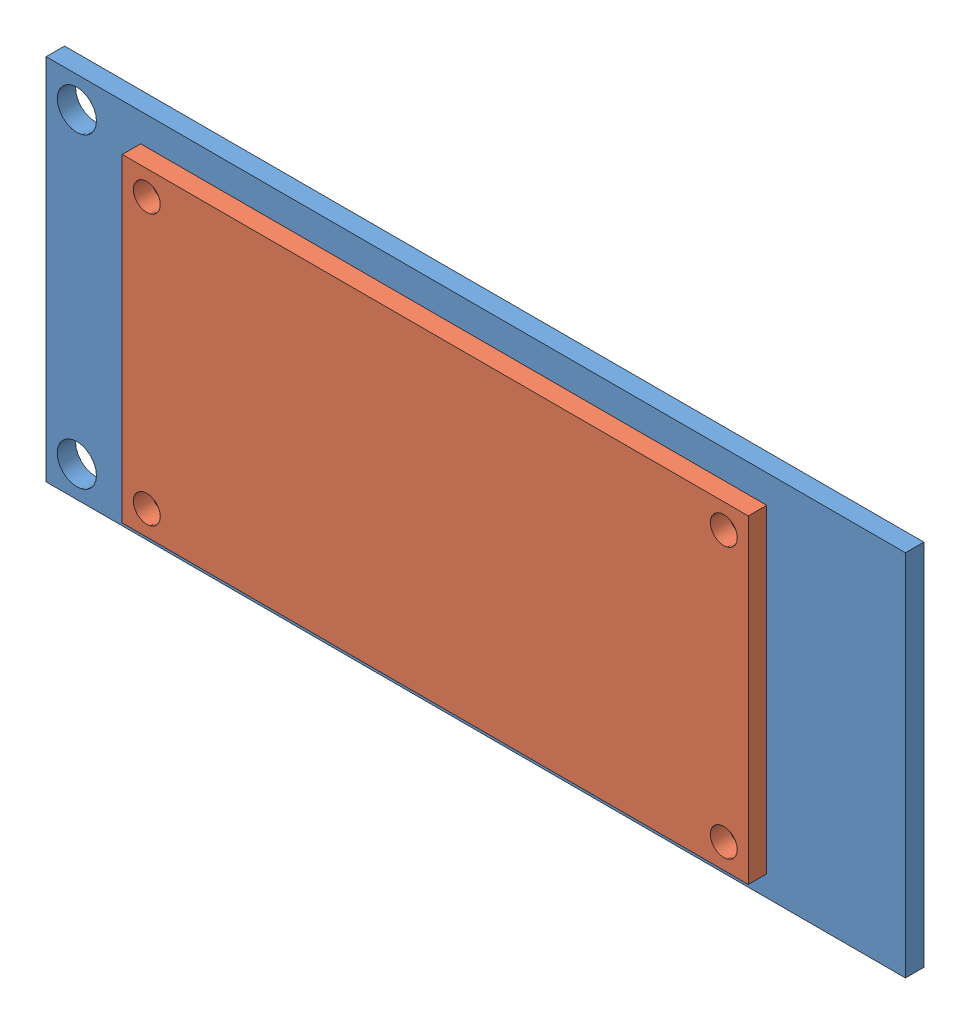
SolidWorks assembly DCDCSB, configuration По умолчанию. Lengths in mm.
Overall size (71.39 30 3.3).
2 component instances, 2 part files, 3 mates.
Components (placement in the parent):
- PodkladkaDCDC-2: PodkladkaDCDC [По умолчанию] x (1 0 0) z (0 -1 0) size (71.39 1.5 30)
- DCDC-1: DCDC [По умолчанию] at (8 2 1.8) x (1 0 0) z (0 -1 0) size (51 1.5 26)
Mates (geometry in assembly coordinates):
- Расстояние1: distance = 0.3 mm anti-aligned: plane of DCDC-1 through (8 2 1.8) normal (0 0 -1); plane of PodkladkaDCDC-2 through (0 0 1.5) normal (0 0 1)
- Концентричный1: concentric aligned: cylinder of PodkladkaDCDC-2 through (10 4 1.5) axis (0 0 -1) radius 1.1; cylinder of DCDC-1 through (10 4 3.3) axis (0 0 -1) radius 1.1
- Концентричный2: concentric aligned: cylinder of PodkladkaDCDC-2 through (57 26 1.5) axis (0 0 -1) radius 1.1; cylinder of DCDC-1 through (57 26 3.3) axis (0 0 -1) radius 1.1
